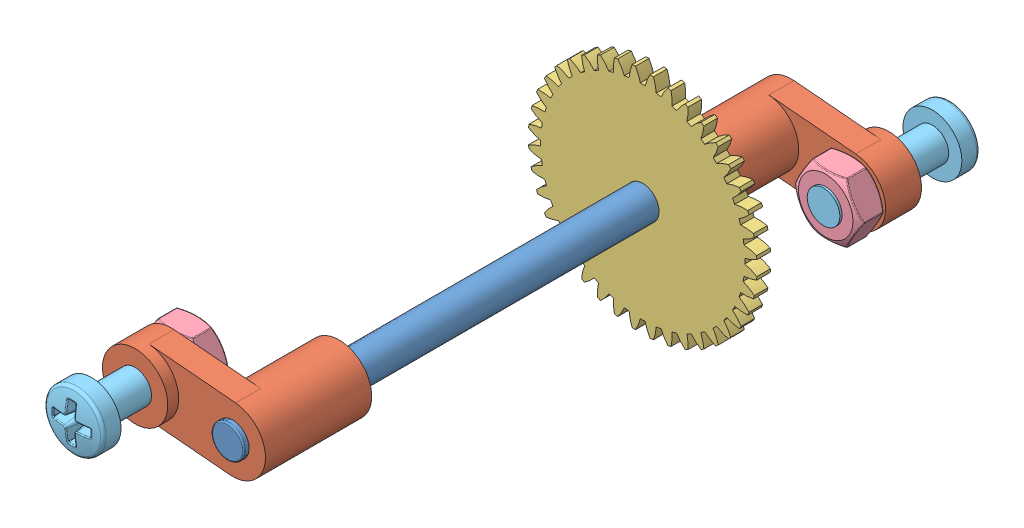
SolidWorks assembly Walking_robot_(assembled_second_axle), configuration Default. Lengths in mm.
Overall size (22.69 20.96 65.22).
8 component instances, 5 part files, 0 mates.
Components (placement in the parent):
- SHAFT 3 X 52-1: SHAFT 3 X 52 [Default] at (-27.916 11.557 0) x (-0.087364 -0.996176 0) z (0 0 1) size (3 3 52)
- ELENCO CRANK ARM 01-1: ELENCO CRANK ARM 01 [Default] at (-27.916 11.557 -23.446) x (0 0 -1) z (-0.996176 0.087364 0) size (10.76 6 14)
- ELENCO CRANK ARM 01-2: ELENCO CRANK ARM 01 [Default] at (-27.916 11.557 23.2184) x (0 0 1) z (0.996176 -0.087364 0) size (10.76 6 14)
- pCOMPOUND GEAR 40T X 10T GREEN R01a-1: pCOMPOUND GEAR 40T X 10T GREEN R01a [Default] at (-27.916 11.557 -12.742) x (0 0 -1) z (1 0 0) size (3.25 20.96 20.96)
- Walking_robot_(nut_3)-1: Walking_robot_(nut_3) [Default] at (-35.8854 12.2559 20.7184) size (6.75 5.87 2.78)
- Walking_robot_(nut_3)-2: Walking_robot_(nut_3) [Default] at (-19.9466 10.8581 -23.446) size (6.75 5.87 2.78)
- Walking_robot_(bolt_3x10)-1: Walking_robot_(bolt_3x10) [Default] at (-35.8854 12.2559 30.5184) x (0 0 1) z (-1 0 0) size (11.98 5.4 5.4)
- Walking_robot_(bolt_3x10)-2: Walking_robot_(bolt_3x10) [Default] at (-19.9466 10.8581 -30.746) x (0 0 -1) z (1 0 0) size (11.98 5.4 5.4)
